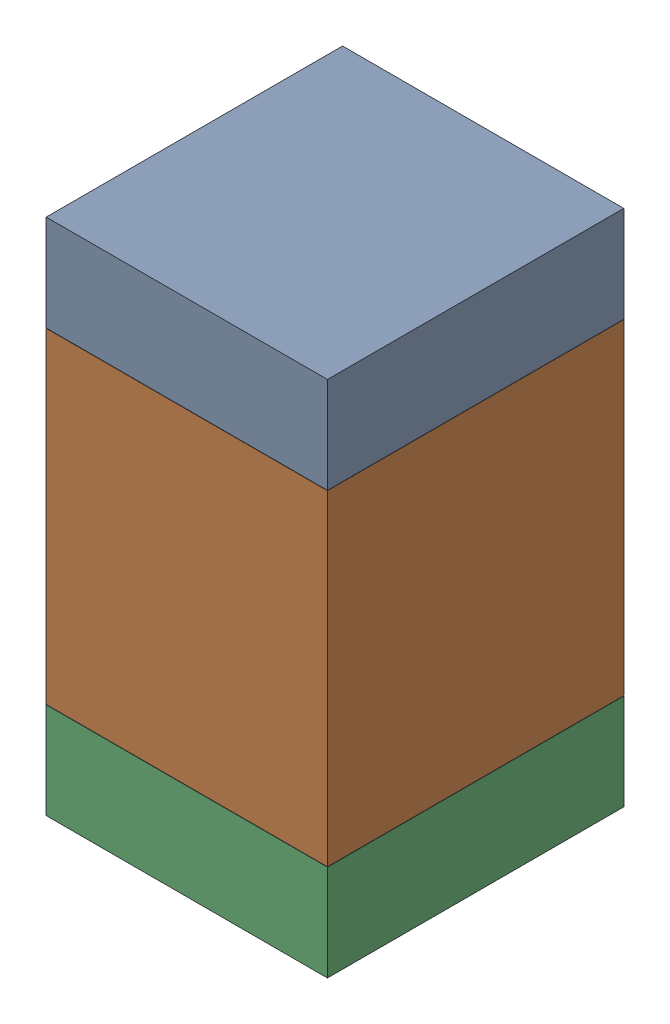
SolidWorks assembly R16, configuration Default. Lengths in mm.
Overall size (0.95 1.75 1).
6 component instances, 2 part files, 0 mates.
Components (placement in the parent):
- 6575495072-1: 6575495072 [Default] at (15.367 12.9045 0) size (0.95 0.32 1)
  - Extruded_6-1: Extruded_6 [Default] at origin size (0.95 0.32 1)
- 6575494912-1: 6575494912 [Default] at (15.367 12.192 0) size (0.95 1.1 1)
  - Extruded_7-1: Extruded_7 [Default] at origin size (0.95 1.1 1)
- 6575495072-2: 6575495072 [Default] at (15.367 11.4795 0) size (0.95 0.32 1)
  - Extruded_6-1: Extruded_6 [Default] at origin size (0.95 0.32 1)
